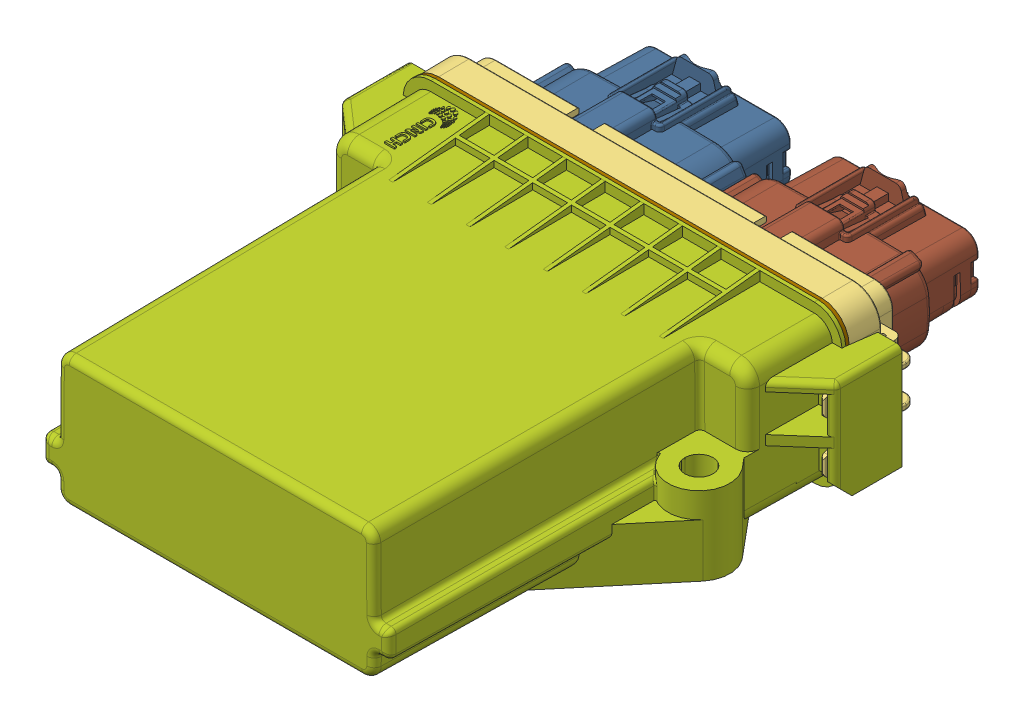
SolidWorks assembly ASSEMPBLY CAIXA PCB C_CONECTORES, configuration Default. Lengths in mm.
Overall size (130.26 42.29 156.72).
57 component instances, 11 part files, 1 mates.
Components (placement in the parent):
- 5810140011_model-1: 5810140011_model [Default] at (-11.4405 -12.1674 14.121) size (126.6 41.34 41.26)
  - 5810140011_model.stp-1: 5810140011_model.stp [Default] at origin size (126.6 41.34 41.26)
    - 4828770271-ME-MX-L20B-R20A_ASM.stp-1: 4828770271-ME-MX-L20B-R20A_ASM.stp [Default] at (0 -1.143 0) x (-1 0 0) z (0 0 -1) size (126.6 41.34 41.26)
      - MOLEX-ME-A-20W_AF2_ASM.stp-1: MOLEX-ME-A-20W_AF2_ASM.stp [Default] at (24.638 1.143 0) size (47 22 28.67)
        - MOLEX-ME-A-20W_AF3.stp-1: MOLEX-ME-A-20W_AF3.stp [Default] at (-17.9886 -11.4851 -14.215) size (47 22 28.67)
      - MOLEX-ME-B-20W_AF2_ASM.stp-1: MOLEX-ME-B-20W_AF2_ASM.stp [Default] at (-24.638 1.143 0) size (47 22 28.67)
        - MOLEX-ME-B-20W_AF3.stp-1: MOLEX-ME-B-20W_AF3.stp [Default] at (-17.9886 -11.4851 -14.215) size (47 22 28.67)
      - 4741170136_MX_ME_L20B-R20A_AF1.stp-1: 4741170136_MX_ME_L20B-R20A_AF1.stp [Default] at origin size (126.6 41.34 27.94)
    - 4040011260_TYPE4.stp-1: 4040011260_TYPE4.stp [Default] at (40.4134 -3.0216 -10.4678) x (-1 0 0) z (0 0 1) size (2.54 8.02 26.57)
    - 4040011261_TYPE5.stp-1: 4040011261_TYPE5.stp [Default] at (40.4134 2.9784 -10.4678) x (-1 0 0) z (0 0 1) size (2.54 14.02 30.56)
    - 4040011260_TYPE4.stp-2: 4040011260_TYPE4.stp [Default] at (8.8626 -3.0216 -10.4678) x (-1 0 0) z (0 0 1) size (2.54 8.02 26.57)
    - 4040011261_TYPE5.stp-2: 4040011261_TYPE5.stp [Default] at (8.8626 3.0419 -10.4678) x (-1 0 0) z (0 0 1) size (2.54 14.02 30.56)
    - 4040011260_TYPE4.stp-3: 4040011260_TYPE4.stp [Default] at (-40.4134 -3.0216 -10.4678) x (-1 0 0) z (0 0 1) size (2.54 8.02 26.57)
    - 4040011261_TYPE5.stp-3: 4040011261_TYPE5.stp [Default] at (-40.4134 3.0419 -10.4678) x (-1 0 0) z (0 0 1) size (2.54 14.02 30.56)
    - 4040011260_TYPE4.stp-4: 4040011260_TYPE4.stp [Default] at (-8.9134 -2.9581 -10.4678) x (-1 0 0) z (0 0 1) size (2.54 8.02 26.57)
    - 4040011261_TYPE5.stp-4: 4040011261_TYPE5.stp [Default] at (-8.8626 3.0419 -10.4678) x (-1 0 0) z (0 0 1) size (2.54 14.02 30.56)
    - 4040011260_TYPE4.stp-5: 4040011260_TYPE4.stp [Default] at (36.8626 -3.0216 -10.4678) x (-1 0 0) z (0 0 1) size (2.54 8.02 26.57)
    - 4040011260_TYPE4.stp-6: 4040011260_TYPE4.stp [Default] at (33.3626 -3.0216 -10.4678) x (-1 0 0) z (0 0 1) size (2.54 8.02 26.57)
    - 4040011260_TYPE4.stp-7: 4040011260_TYPE4.stp [Default] at (29.8626 -3.0216 -10.4678) x (-1 0 0) z (0 0 1) size (2.54 8.02 26.57)
    - 4040011260_TYPE4.stp-8: 4040011260_TYPE4.stp [Default] at (26.3626 -3.0216 -10.4678) x (-1 0 0) z (0 0 1) size (2.54 8.02 26.57)
    - 4040011260_TYPE4.stp-9: 4040011260_TYPE4.stp [Default] at (22.8626 -3.0216 -10.4678) x (-1 0 0) z (0 0 1) size (2.54 8.02 26.57)
    - 4040011260_TYPE4.stp-10: 4040011260_TYPE4.stp [Default] at (19.3626 -3.0216 -10.4678) x (-1 0 0) z (0 0 1) size (2.54 8.02 26.57)
    - 4040011260_TYPE4.stp-11: 4040011260_TYPE4.stp [Default] at (15.8626 -3.0216 -10.4678) x (-1 0 0) z (0 0 1) size (2.54 8.02 26.57)
    - 4040011260_TYPE4.stp-12: 4040011260_TYPE4.stp [Default] at (12.3626 -3.0216 -10.4678) x (-1 0 0) z (0 0 1) size (2.54 8.02 26.57)
    - 4040011260_TYPE4.stp-13: 4040011260_TYPE4.stp [Default] at (-12.4134 -3.0216 -10.4678) x (-1 0 0) z (0 0 1) size (2.54 8.02 26.57)
    - 4040011260_TYPE4.stp-14: 4040011260_TYPE4.stp [Default] at (-15.9134 -3.0216 -10.4678) x (-1 0 0) z (0 0 1) size (2.54 8.02 26.57)
    - 4040011260_TYPE4.stp-15: 4040011260_TYPE4.stp [Default] at (-19.4134 -3.0216 -10.4678) x (-1 0 0) z (0 0 1) size (2.54 8.02 26.57)
    - 4040011260_TYPE4.stp-16: 4040011260_TYPE4.stp [Default] at (-22.9134 -3.0216 -10.4678) x (-1 0 0) z (0 0 1) size (2.54 8.02 26.57)
    - 4040011260_TYPE4.stp-17: 4040011260_TYPE4.stp [Default] at (-26.4134 -3.0216 -10.4678) x (-1 0 0) z (0 0 1) size (2.54 8.02 26.57)
    - 4040011260_TYPE4.stp-18: 4040011260_TYPE4.stp [Default] at (-29.9134 -3.0216 -10.4678) x (-1 0 0) z (0 0 1) size (2.54 8.02 26.57)
    - 4040011260_TYPE4.stp-19: 4040011260_TYPE4.stp [Default] at (-33.4134 -3.0216 -10.4678) x (-1 0 0) z (0 0 1) size (2.54 8.02 26.57)
    - 4040011260_TYPE4.stp-20: 4040011260_TYPE4.stp [Default] at (-36.9134 -3.0216 -10.4678) x (-1 0 0) z (0 0 1) size (2.54 8.02 26.57)
    - 4040011261_TYPE5.stp-5: 4040011261_TYPE5.stp [Default] at (36.8626 3.0419 -10.4678) x (-1 0 0) z (0 0 1) size (2.54 14.02 30.56)
    - 4040011261_TYPE5.stp-6: 4040011261_TYPE5.stp [Default] at (33.3626 3.0419 -10.4678) x (-1 0 0) z (0 0 1) size (2.54 14.02 30.56)
    - 4040011261_TYPE5.stp-7: 4040011261_TYPE5.stp [Default] at (29.8626 3.0419 -10.4678) x (-1 0 0) z (0 0 1) size (2.54 14.02 30.56)
    - 4040011261_TYPE5.stp-8: 4040011261_TYPE5.stp [Default] at (26.3626 3.0419 -10.4678) x (-1 0 0) z (0 0 1) size (2.54 14.02 30.56)
    - 4040011261_TYPE5.stp-9: 4040011261_TYPE5.stp [Default] at (22.8626 3.0419 -10.4678) x (-1 0 0) z (0 0 1) size (2.54 14.02 30.56)
    - 4040011261_TYPE5.stp-10: 4040011261_TYPE5.stp [Default] at (19.3626 3.0419 -10.4678) x (-1 0 0) z (0 0 1) size (2.54 14.02 30.56)
    - 4040011261_TYPE5.stp-11: 4040011261_TYPE5.stp [Default] at (15.8626 3.0419 -10.4678) x (-1 0 0) z (0 0 1) size (2.54 14.02 30.56)
    - 4040011261_TYPE5.stp-12: 4040011261_TYPE5.stp [Default] at (12.3626 3.0419 -10.4678) x (-1 0 0) z (0 0 1) size (2.54 14.02 30.56)
    - 4040011261_TYPE5.stp-13: 4040011261_TYPE5.stp [Default] at (-12.4134 3.0419 -10.4678) x (-1 0 0) z (0 0 1) size (2.54 14.02 30.56)
    - 4040011261_TYPE5.stp-14: 4040011261_TYPE5.stp [Default] at (-15.9134 3.0419 -10.4678) x (-1 0 0) z (0 0 1) size (2.54 14.02 30.56)
    - 4040011261_TYPE5.stp-15: 4040011261_TYPE5.stp [Default] at (-19.4134 3.0419 -10.4678) x (-1 0 0) z (0 0 1) size (2.54 14.02 30.56)
    - 4040011261_TYPE5.stp-16: 4040011261_TYPE5.stp [Default] at (-22.9134 3.0419 -10.4678) x (-1 0 0) z (0 0 1) size (2.54 14.02 30.56)
    - 4040011261_TYPE5.stp-17: 4040011261_TYPE5.stp [Default] at (-26.4134 3.0419 -10.4678) x (-1 0 0) z (0 0 1) size (2.54 14.02 30.56)
    - 4040011261_TYPE5.stp-18: 4040011261_TYPE5.stp [Default] at (-29.9134 3.0419 -10.4678) x (-1 0 0) z (0 0 1) size (2.54 14.02 30.56)
    - 4040011261_TYPE5.stp-19: 4040011261_TYPE5.stp [Default] at (-33.4134 3.0419 -10.4678) x (-1 0 0) z (0 0 1) size (2.54 14.02 30.56)
    - 4040011261_TYPE5.stp-20: 4040011261_TYPE5.stp [Default] at (-36.9134 3.0419 -10.4678) x (-1 0 0) z (0 0 1) size (2.54 14.02 30.56)
    - ME-MX-20W-POTTING.stp-1: ME-MX-20W-POTTING.stp [Default] at (24.638 0 9) x (1 0 0) z (0 -1 0) size (35 6.97 8.4)
    - ME-MX-20W-POTTING.stp-2: ME-MX-20W-POTTING.stp [Default] at (-24.638 0 9) x (1 0 0) z (0 -1 0) size (35 6.97 8.4)
- 5810130065_rev_B-1: 5810130065_rev_B [Default] at (-11.3655 -13.0872 19.709) x (-1 0 0) z (0 0 -1) size (130.26 42.29 116.81)
  - 5810130065_rev_B.stp-1: 5810130065_rev_B.stp [Default] at origin size (130.26 42.29 116.81)
    - 4828770226.stp-1: 4828770226.stp [Default] at origin size (130.26 42.29 116.81)
    - 4630899185_STRETCHED.stp-1: 4630899185_STRETCHED.stp [Default] at (0 0 2.54) size (112.73 38.37 7.62)
    - 4630899186_STRETCHED.stp-1: 4630899186_STRETCHED.stp [Default] at (0 0 -3.81) size (115.27 41.17 6.3)
- MOLEX 0334722006  KEY A-1: MOLEX 0334722006  KEY A [Default] at (-36.084 -12.3106 9.7328) size (49.15 24.88 37.15)
- MOLEX 0334722007 KEY B-1: MOLEX 0334722007 KEY B [Default] at (13.5619 -12.4311 10.0397) size (47.9 24.88 37.19)
Mates (geometry in assembly coordinates):
- Coincident1: coincident: plane of 5810140011_model-1/5810140011_model.stp-1/4828770271-ME-MX-L20B-R20A_ASM.stp-1/4741170136_MX_ME_L20B-R20A_AF1.stp-1 through (-11.4405 -13.3104 16.153) normal (0 0 1); plane of 5810130065_rev_B-1/5810130065_rev_B.stp-1/4828770226.stp-1 through (-11.3655 -13.0872 16.153) normal (0 0 -1)
